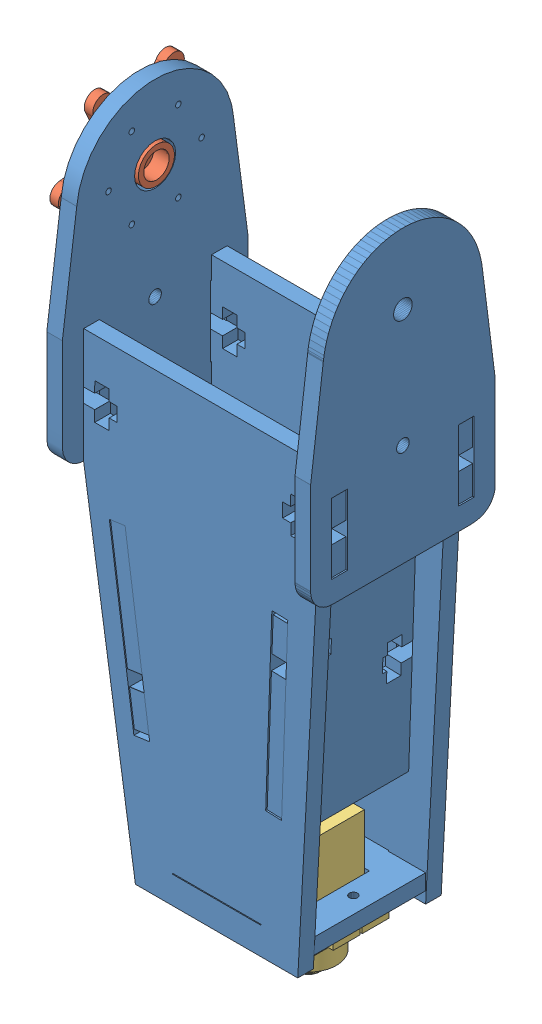
SolidWorks assembly Assem1, configuration Default. Lengths in mm.
Overall size (61.69 161.79 48.67).
3 component instances, 3 part files, 2 mates.
Components (placement in the parent):
- right_forearm_100-1: right_forearm_100 [Default] at origin size (59.26 143.78 48.67)
- servo_arm_6_sided-1: servo_arm_6_sided [Default] at (-0.3355 127.463 16.183) x (0 -0.873408 0.48699) z (0 -0.48699 -0.873408) size (36.45 6.25 32.2)
- MG90S-1: MG90S [Default] at (33.1192 19.8275 16.8558) x (1 -0.00011 0) z (0 0 -1) size (34 30.4 12.5)
Mates (geometry in assembly coordinates):
- ProfileCenter1: profile center anti-aligned: circle of right_forearm_100-1; circle of servo_arm_6_sided-1
- Coincident1: coincident anti-aligned: line of right_forearm_100-1 through (44.6174 3.8262 22.6073) axis (0 0 -1); line of MG90S-1 through (44.6174 3.8262 10.6058) axis (0 0 1)
